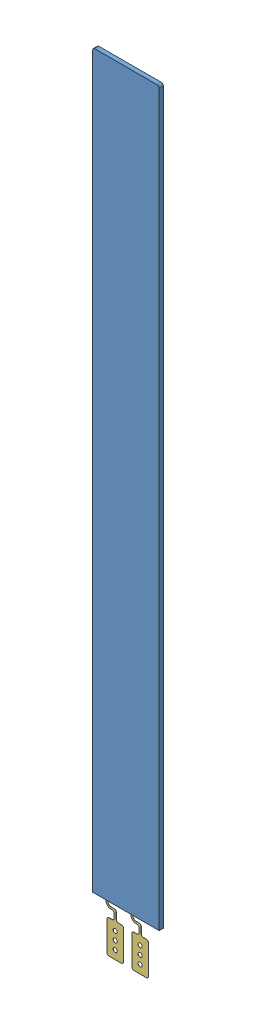
SolidWorks assembly Strain_Sensor_Assembly-X01, configuration Default. Lengths in mm.
Overall size (8 93.95 0.5).
3 component instances, 3 part files, 6 mates.
Components (placement in the parent):
- PDMS_Encapsulation-Strain_Sensor-X01-1: PDMS_Encapsulation-Strain_Sensor-X01 [Default] at (3.9812 54.5762 54.2607) size (8 88 0.51)
- Strain_Sensor-AgNW-X01-1: Strain_Sensor-AgNW-X01 [V2] at (3.9191 21.0012 54.2607) x (0 -1 0) z (0 0 1) size (38.08 5.15 0.02)
- Copper_Interconnects-Strain-X01-1: Copper_Interconnects-Strain-X01 [Default] at (3.9191 20.7512 54.2757) x (0 1 0) z (0 0 1) size (58.12 5.25 0.02)
Mates (geometry in assembly coordinates):
- Coincident1: coincident anti-aligned: plane of PDMS_Encapsulation-Strain_Sensor-X01-1 through (3.9812 54.5762 54.2607) normal (0 0 1); plane of Strain_Sensor-AgNW-X01-1 through (3.9191 21.0012 54.2607) normal (0 0 -1)
- Parallel1: parallel aligned: plane of Strain_Sensor-AgNW-X01-1 through (3.9191 21.0012 54.2607) normal (1 0 0)
- Distance1: distance = 0.25 mm anti-aligned: plane of Strain_Sensor-AgNW-X01-1 through (3.9191 57.0762 51.2202) normal (0 1 0); plane of PDMS_Encapsulation-Strain_Sensor-X01-1 through (3.9812 57.3262 54.3657) normal (0 -1 0)
- Coincident5: coincident anti-aligned: plane of Strain_Sensor-AgNW-X01-1 through (3.9191 21.0012 54.2757) normal (0 0 1); plane of Copper_Interconnects-Strain-X01-1 through (3.9191 20.7512 54.2757) normal (0 0 -1)
- Coincident6: coincident aligned: plane of Strain_Sensor-AgNW-X01-1 through (3.4191 23.0012 54.2757) normal (1 0 0); plane of Copper_Interconnects-Strain-X01-1 through (3.4191 18.7512 54.2907) normal (1 0 0)
- Distance2: distance = 0.25 mm aligned: plane of Copper_Interconnects-Strain-X01-1 through (6.4191 22.7512 54.2907) normal (0 1 0); plane of Strain_Sensor-AgNW-X01-1 through (4.4191 23.0012 54.2757) normal (0 1 0)
